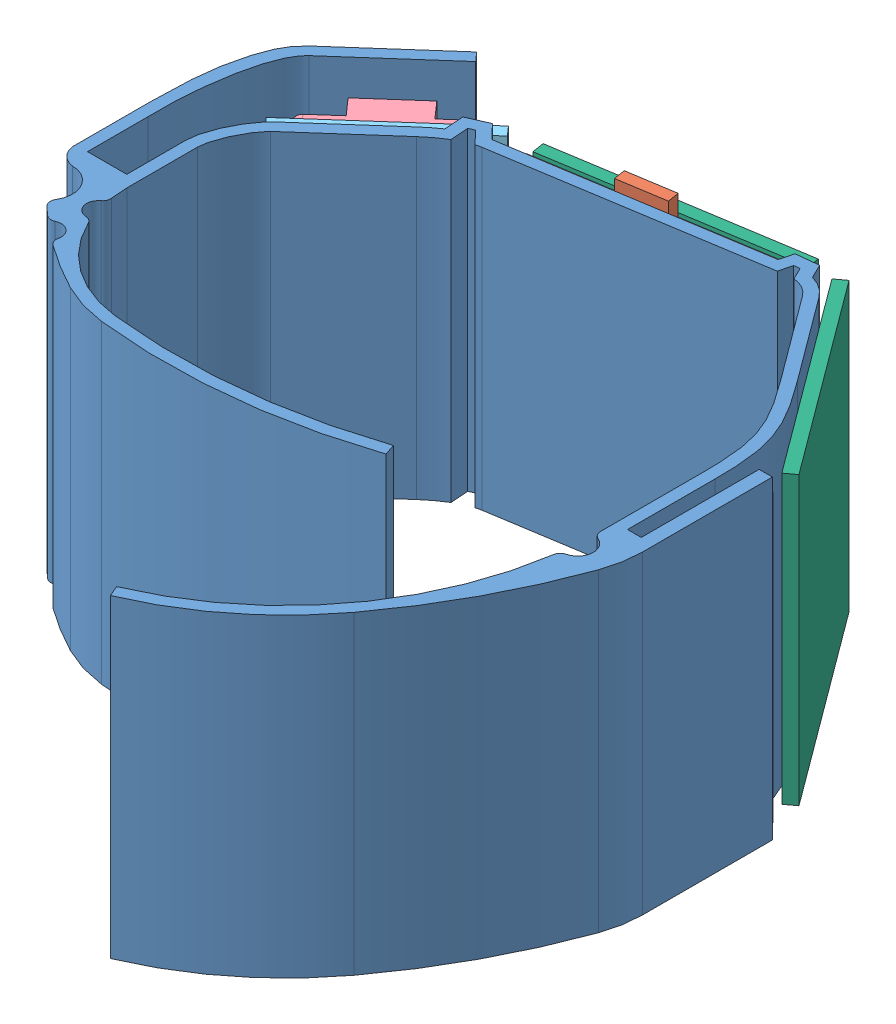
SolidWorks assembly Assembly, configuration Default. Lengths in mm.
Overall size (74.71 40 45.45).
9 component instances, 8 part files, 18 mates.
Components (placement in the parent):
- Underbelly-1: Underbelly [Default] at (-94.5076 0 32.7072) size (80.94 40 83.21)
- Battery - 500 mAh-1: Battery - 500 mAh [Default] at (-44.7217 0 -0.9949) x (0 1 0) z (0.987667 0 -0.156567) size (40 4.64 30)
- BLE-1: BLE [Default] at (-93.5328 31.88 18.0904) x (0 -1 0) z (-0.749403 0 0.662114) size (31.88 4.03 21.4)
- ItsyBitsy-1: ItsyBitsy [Default] at (-79.421 35.86 3.5406) x (0 -1 0) z (0.749403 0 -0.662114) size (35.86 4.4 17.78)
- PCB - BLE-1: PCB - BLE [Default] at (-78.0426 0 2.3229) x (0 1 0) z (0.749403 0 -0.662114) size (36.5 1.56 21.84)
- PCB - Buttons-1: PCB - Buttons [Default] at (-73.6594 36.5 3.5923) x (0.987667 0 -0.156567) z (0 1 0) size (30.6 1.56 36.5)
- PCB - LiPo-1: PCB - LiPo [Default] at (-95.0676 36.5 35.4227) x (0 -1 0) z (0 0 1) size (36.5 1.56 16)
- PCB - Status-1: PCB - Status [Default] at (-22.5076 36.5 42.5202) x (0 -1 0) z (0 0 1) size (36.5 1.56 16.76)
- PCB - Buttons-2: PCB - Buttons [Default] at (-39.363 0 -2.3444) x (0.595135 0 0.803626) z (0 -1 0) size (30.6 1.56 36.5)
Mates (geometry in assembly coordinates):
- Coincident1: coincident anti-aligned: plane of Underbelly-1 through (-39.7779 0 7.775) normal (0 -1 0)
- Coincident2: coincident anti-aligned: plane of Underbelly-1 through (-39.7779 0 7.775) normal (0 -1 0)
- Coincident3: coincident anti-aligned: plane of Battery - 500 mAh-1 through (-43.9952 0 3.5878) normal (0 -1 0)
- Coincident7: coincident anti-aligned: plane of Underbelly-1 through (-74.1095 36.5 8.3616) normal (-0.156567 0 -0.987667); plane of Battery - 500 mAh-1 through (-43.9952 0 3.5878) normal (0.156567 0 0.987667)
- Coincident8: coincident anti-aligned: plane of BLE-1 through (-92.5396 0 19.2145) normal (0 -1 0)
- Coincident9: coincident anti-aligned: plane of Underbelly-1 through (-90.0939 36.5 20.4297) normal (-0.662114 0 -0.749403); plane of BLE-1 through (-90.8645 31.88 21.1105) normal (0.662114 0 0.749403)
- Coincident10: coincident anti-aligned: plane of BLE-1 through (-93.5328 31.88 18.0904) normal (-0.662114 0 -0.749403); plane of PCB - BLE-1 through (-77.0097 0 3.4919) normal (0.662114 0 0.749403)
- Coincident11: coincident anti-aligned: plane of PCB - BLE-1 through (-77.0097 0 3.4919) normal (0 -1 0)
- Coincident12: coincident anti-aligned: plane of ItsyBitsy-1 through (-80.4803 0 2.3416) normal (0 -1 0)
- Coincident13: coincident anti-aligned: plane of ItsyBitsy-1 through (-79.421 35.86 3.5406) normal (0.662114 0 0.749403); plane of PCB - BLE-1 through (-78.0426 0 2.3229) normal (-0.662114 0 -0.749403)
- Coincident14: coincident anti-aligned: plane of Battery - 500 mAh-1 through (-44.7217 0 -0.9949) normal (-0.156567 0 -0.987667); plane of PCB - Buttons-1 through (-73.6594 36.5 3.5923) normal (0.156567 0 0.987667)
- Coincident15: coincident anti-aligned: plane of PCB - Buttons-1 through (-73.9036 0 2.0516) normal (0 -1 0)
- Coincident16: coincident anti-aligned: plane of PCB - Buttons-2 through (-40.6167 0 -1.416) normal (0 -1 0)
- Coincident18: coincident anti-aligned: plane of PCB - Status-1 through (-20.9476 0 42.5202) normal (0 -1 0)
- Coincident19: coincident anti-aligned: plane of PCB - LiPo-1 through (-93.5076 0 35.4227) normal (0 -1 0)
- Coincident20: coincident anti-aligned: plane of Underbelly-1 through (-93.5076 36.5 32.7072) normal (-1 0 0); plane of PCB - LiPo-1 through (-93.5076 36.5 35.4227) normal (1 0 0)
- Coincident21: coincident anti-aligned: plane of Underbelly-1 through (-22.5076 36.5 42.7072) normal (1 0 0); plane of PCB - Status-1 through (-22.5076 36.5 42.5202) normal (-1 0 0)
- Coincident22: coincident anti-aligned: plane of Underbelly-1 through (-35.9238 36.5 4.9209) normal (0.803626 0 -0.595135); plane of PCB - Buttons-2 through (-40.6167 0 -1.416) normal (-0.803626 0 0.595135)
